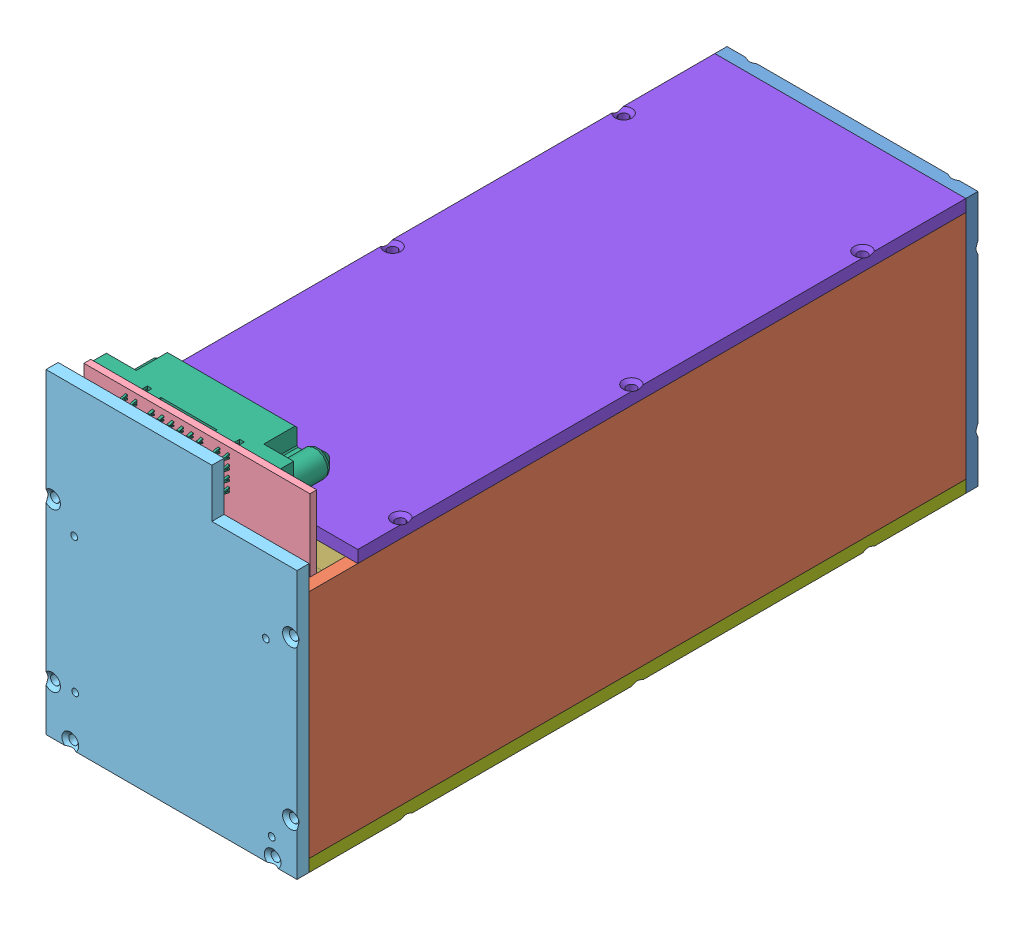
SolidWorks assembly battbox, configuration Default. Lengths in mm.
Overall size (65.53 82.72 178.14).
14 component instances, 8 part files, 38 mates.
Components (placement in the parent):
- battbox_back-1: battbox_back [Default] at (28.2408 39.3364 -78.3001) x (-1 0 0) z (0 -1 0) size (65.53 3.34 66.67)
- battbox_side-1: battbox_side [Default] at (-1.3502 39.3364 7.4249) x (0 1 0) z (0 0 1) size (60.32 3.17 171.45)
- battbox_side-2: battbox_side [Default] at (57.8318 39.3364 7.4249) x (0 -1 0) z (0 0 1) size (60.32 3.17 171.45)
- LiPoBattery-3.7V-1: LiPoBattery-3.7V [Default] at (28.1498 14.4989 -78.3001) x (0 -1 0) z (0 0 1) size (10 59 155)
- LiPoBattery-3.7V-2: LiPoBattery-3.7V [Default] at (28.1498 24.4989 -78.3001) x (0 1 0) z (0 0 1) size (10 59 155)
- LiPoBattery-3.7V-3: LiPoBattery-3.7V [Default] at (28.1498 54.4989 -78.3001) x (0 1 0) z (0 0 1) size (10 59 155)
- LiPoBattery-3.7V-4: LiPoBattery-3.7V [Default] at (28.1498 34.4989 -78.3001) x (0 1 0) z (0 0 1) size (10 59 155)
- LiPoBattery-3.7V-5: LiPoBattery-3.7V [Default] at (28.1498 44.4989 -78.3001) x (0 1 0) z (0 0 1) size (10 59 155)
- LiPoBattery-3.7V-6: LiPoBattery-3.7V [Default] at (28.1498 64.4989 -78.3001) x (0 1 0) z (0 0 1) size (10 59 155)
- battery_board-1: battery_board [Default] at (28.1498 47.6739 87.8159) size (59 79 1.78)
- battbox_front-1: battbox_front [Default] at (28.2408 39.3364 93.1499) x (1 0 0) z (0 -1 0) size (65.53 3.34 82.55)
- molex_connector_876951001-1: molex_connector_876951001 [Default] at (23.0998 81.4859 81.4659) x (1 0 0) z (0 1 0) size (48.9 20.45 12.09)
- battbox_base-3: battbox_base [Default] at (28.2408 9.1739 7.4249) x (-1 0 0) z (0 0 1) size (65.53 3.34 171.45)
- battbox_top-2: battbox_top [Default] at (28.2408 69.4989 1.0749) size (65.53 3.34 158.75)
Mates (geometry in assembly coordinates):
- Coincident16: coincident: plane of battbox_back-1 through (61.0068 5.9989 -78.3001) normal (0 0 1); line of LiPoBattery-3.7V-1 through (57.6498 19.4989 -78.3001) axis (-1 0 0)
- Coincident17: coincident anti-aligned: plane of battbox_side-1 through (-1.3502 9.1739 -78.3001) normal (1 0 0); plane of LiPoBattery-3.7V-1 through (-1.3502 19.4989 76.6999) normal (-1 0 0)
- Coincident18: coincident anti-aligned: plane of LiPoBattery-3.7V-1 through (57.6498 19.4989 76.6999) normal (0 1 0); plane of LiPoBattery-3.7V-2
- Coincident19: coincident anti-aligned: plane of LiPoBattery-3.7V-2 through (-1.3502 29.4989 76.6999) normal (0 1 0); plane of LiPoBattery-3.7V-4
- Coincident20: coincident anti-aligned: plane of assembly through (-1.3502 39.4989 76.6999) normal (0 1 0)
- Coincident21: coincident anti-aligned: plane of assembly through (-1.3502 49.4989 76.6999) normal (0 1 0)
- Coincident22: coincident anti-aligned: plane of assembly through (-1.3502 59.4989 76.6999) normal (0 1 0)
- Coincident23: coincident aligned: plane of LiPoBattery-3.7V-3 through (-1.3502 49.4989 76.6999) normal (-1 0 0); plane of LiPoBattery-3.7V-6 through (-1.3502 59.4989 76.6999) normal (-1 0 0)
- Coincident24: coincident aligned: plane of LiPoBattery-3.7V-3 through (-1.3502 49.4989 76.6999) normal (-1 0 0); plane of LiPoBattery-3.7V-5 through (-1.3502 39.4989 76.6999) normal (-1 0 0)
- Coincident25: coincident aligned: plane of LiPoBattery-3.7V-4 through (-1.3502 29.4989 76.6999) normal (-1 0 0); plane of LiPoBattery-3.7V-5 through (-1.3502 39.4989 76.6999) normal (-1 0 0)
- Coincident26: coincident aligned: plane of LiPoBattery-3.7V-2 through (-1.3502 19.4989 76.6999) normal (-1 0 0); plane of LiPoBattery-3.7V-4 through (-1.3502 29.4989 76.6999) normal (-1 0 0)
- Coincident27: coincident aligned: plane of LiPoBattery-3.7V-2 through (57.6498 19.4989 76.6999) normal (0 0 1); plane of LiPoBattery-3.7V-4 through (57.6498 29.4989 76.6999) normal (0 0 1)
- Coincident28: coincident aligned: plane of LiPoBattery-3.7V-4 through (57.6498 29.4989 76.6999) normal (0 0 1); plane of LiPoBattery-3.7V-5 through (57.6498 39.4989 76.6999) normal (0 0 1)
- Coincident29: coincident aligned: plane of LiPoBattery-3.7V-3 through (57.6498 49.4989 76.6999) normal (0 0 1); plane of LiPoBattery-3.7V-5 through (57.6498 39.4989 76.6999) normal (0 0 1)
- Coincident30: coincident aligned: plane of LiPoBattery-3.7V-3 through (57.6498 49.4989 76.6999) normal (0 0 1); plane of LiPoBattery-3.7V-6 through (57.6498 59.4989 76.6999) normal (0 0 1)
- Coincident31: coincident aligned: plane of LiPoBattery-3.7V-1 through (-1.3502 19.4989 76.6999) normal (0 0 1); plane of LiPoBattery-3.7V-2 through (57.6498 19.4989 76.6999) normal (0 0 1)
- Coincident32: coincident anti-aligned: plane of battbox_side-1 through (-1.3502 9.1739 -78.3001) normal (1 0 0); plane of LiPoBattery-3.7V-2 through (-1.3502 19.4989 76.6999) normal (-1 0 0)
- Coincident45: coincident anti-aligned: plane of battbox_side-1 through (-1.3502 9.1739 -78.3001) normal (1 0 0); plane of battery_board-1 through (-1.3502 88.1739 89.5939) normal (-1 0 0)
- Distance2: distance = 3.556 mm anti-aligned: plane of battery_board-1 through (-1.3502 9.1739 89.5939) normal (0 0 1); plane of battbox_front-1 through (-4.5252 5.9989 93.1499) normal (0 0 -1)
- Coincident57: coincident anti-aligned: plane of battery_board-1 through (-1.3502 9.1739 87.8159) normal (0 0 -1); plane of molex_connector_876951001-1 through (-1.3502 87.5309 87.8159) normal (0 0 1)
- Coincident58: coincident aligned: plane of battery_board-1 through (-1.3502 88.1739 89.5939) normal (-1 0 0); plane of molex_connector_876951001-1 through (-1.3502 81.4859 81.4659) normal (-1 0 0)
- Distance3: distance = 0.643 mm aligned: plane of battery_board-1 through (-1.3502 88.1739 89.5939) normal (0 1 0); plane of molex_connector_876951001-1 through (-1.3502 87.5309 75.1159) normal (0 1 0)
- Parallel1: parallel aligned: plane of LiPoBattery-3.7V-1; plane of battbox_base-3
- Coincident64: coincident anti-aligned: plane of battbox_side-1 through (-4.5252 9.1739 -78.3001) normal (0 -1 0); plane of battbox_base-3 through (61.0068 9.1739 93.1499) normal (0 1 0)
- Concentric15: concentric aligned: circle of battbox_side-1; circle of battbox_base-3
- Concentric16: concentric aligned: circle of battbox_side-1; circle of battbox_base-3
- Coincident66: coincident anti-aligned: plane of battbox_side-2; plane of battbox_top-2 through (-4.5252 69.4989 -78.3001) normal (0 -1 0)
- Coincident67: coincident anti-aligned: plane of battbox_side-2 through (61.0068 9.1739 -78.3001) normal (0 -1 0); plane of battbox_base-3 through (61.0068 9.1739 93.1499) normal (0 1 0)
- Parallel2: parallel aligned: plane of battbox_side-1 through (-4.5252 9.1739 -78.3001) normal (-1 0 0); plane of battbox_top-2 through (-4.5252 72.6739 -78.3001) normal (-1 0 0)
- Concentric17: concentric aligned: circle of battbox_side-2; circle of battbox_top-2
- Coincident68: coincident anti-aligned: line of battbox_back-1 through (61.0068 72.6739 -78.3001) axis (0 -1 0); line of battbox_side-2 through (61.0068 9.1739 -78.3001) axis (0 1 0)
- Coincident69: coincident anti-aligned: line of battbox_side-2 through (61.0068 69.4989 93.1499) axis (0 -1 0); line of battbox_front-1 through (61.0068 5.9989 93.1499) axis (0 1 0)
- Concentric18: concentric aligned: circle of battbox_back-1; circle of battbox_top-2
- Coincident70: coincident anti-aligned: plane of LiPoBattery-3.7V-6 through (-1.3502 69.4989 76.6999) normal (0 1 0); plane of battbox_top-2 through (-4.5252 69.4989 -78.3001) normal (0 -1 0)
- Coincident71: coincident anti-aligned: plane of battery_board-1 through (-1.3502 9.1739 89.5939) normal (0 -1 0); plane of battbox_base-3 through (61.0068 9.1739 93.1499) normal (0 1 0)
- Concentric19: concentric aligned: circle of battbox_side-2; circle of battbox_front-1
- Concentric20: concentric aligned: circle of battbox_side-1; circle of battbox_front-1
- Coincident72: coincident anti-aligned: plane of battbox_side-1 through (-4.5252 9.1739 93.1499) normal (0 0 1); plane of battbox_front-1 through (-4.5252 5.9989 93.1499) normal (0 0 -1)
